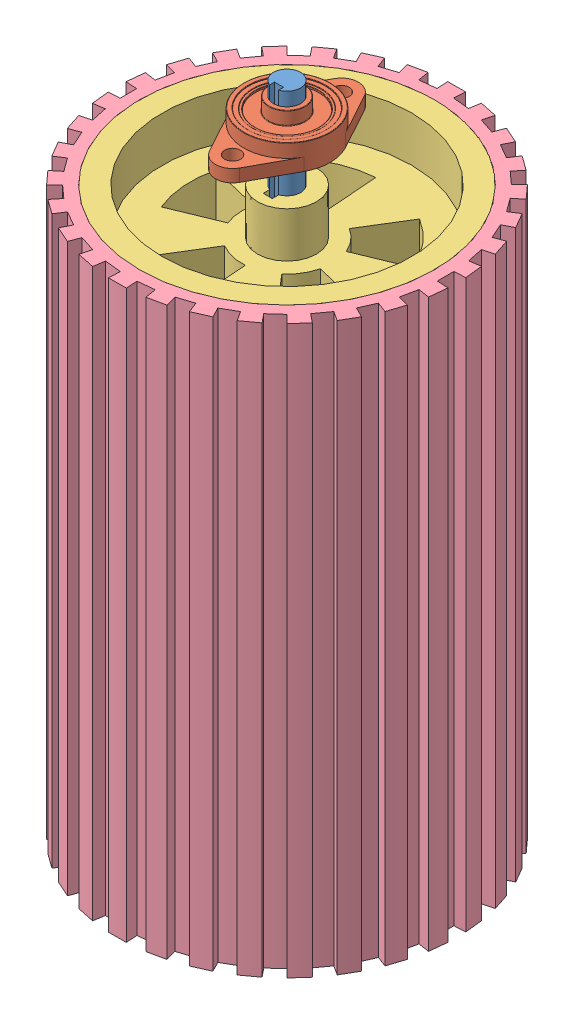
SolidWorks assembly wheel with block flange assembly, configuration Default. Lengths in mm.
Overall size (149.8 290 150).
5 component instances, 4 part files, 5 mates.
Components (placement in the parent):
- support wheel shaft-1: support wheel shaft [Default] at (42.428 -109.2206 52.657) size (12 290 12)
- KFL001 block flange ball bearing 12 diameter shaft-1: KFL001 block flange ball bearing 12 diameter shaft [Default] at (42.428 122.7794 52.657) size (38 16 63)
- wheel assembly 250mm-1: wheel assembly 250mm [Default] at (109.3345 -177.8583 324.9521) x (-1 0 0) z (0 0 -1) size (149.8 250 150)
  - wheel rim-1: wheel rim [Default] at (66.9065 32.6377 272.2951) size (130 250 130)
  - wheel rubber-1: wheel rubber [Default] at (66.9065 32.6377 272.2951) size (149.8 250 150)
Mates (geometry in assembly coordinates):
- Coincident1: coincident aligned: plane of support wheel shaft-1 through (42.428 -145.2206 52.657) normal (0 -1 0); plane of wheel assembly 250mm-1/wheel rim-1 through (42.428 -145.2206 52.657) normal (0 -1 0)
- Coincident2: coincident anti-aligned: line of support wheel shaft-1 through (40.428 -145.2206 58.3138) axis (0 0 -1); line of wheel assembly 250mm-1/wheel rim-1 through (40.428 -145.2206 58.3138) axis (0 0 1)
- Concentric1: concentric aligned: circle of support wheel shaft-1; circle of wheel assembly 250mm-1/wheel rim-1
- Concentric2: concentric aligned: circle of support wheel shaft-1; circle of KFL001 block flange ball bearing 12 diameter shaft-1
- Distance1: distance = 18 mm anti-aligned: plane of wheel assembly 250mm-1/wheel rim-1 through (42.428 104.7794 52.657) normal (0 1 0); plane of KFL001 block flange ball bearing 12 diameter shaft-1 through (42.428 122.7794 52.657) normal (0 -1 0)
